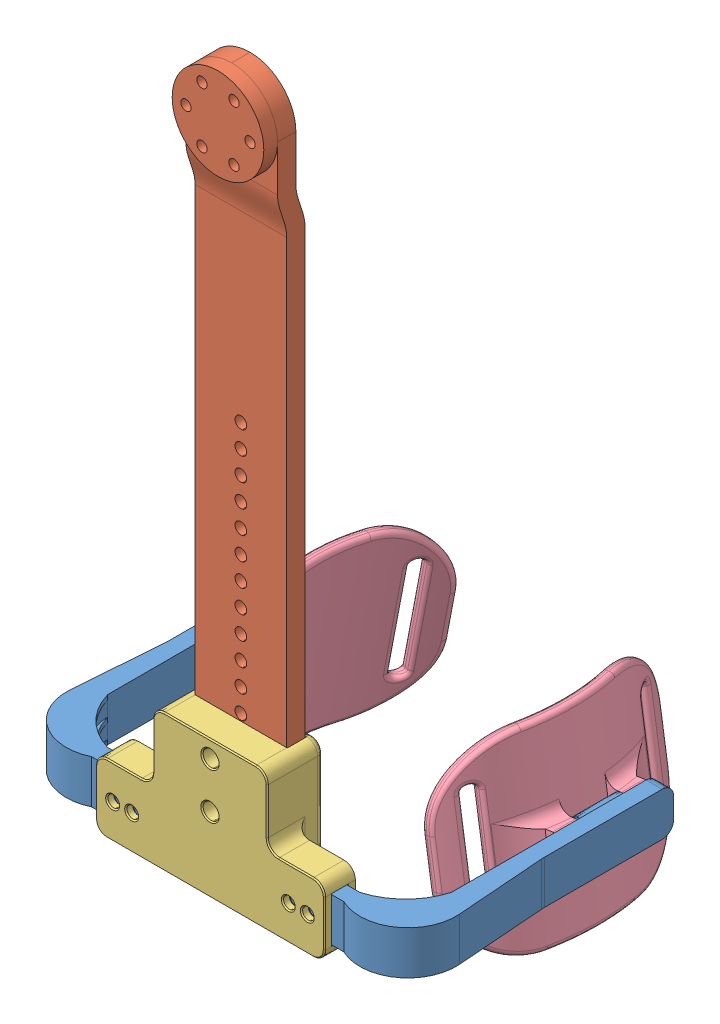
SolidWorks assembly Running_exo_edits_June_10th_2024, configuration Default. Lengths in mm.
Overall size (169.95 340.24 151.32).
6 component instances, 4 part files, 11 mates.
Components (placement in the parent):
- Lshape-thigh_running_v4-2: Lshape-thigh_running_v4 [Default] at (181.1168 78.6919 18.3806) x (0 0 1) z (-1 0 0) size (120 19 75.06)
- Lshape-thigh_running_v4-3: Lshape-thigh_running_v4 [Default] at (17.2912 97.6919 18.6306) x (0 0 1) z (1 0 0) size (120 19 75.06)
- RotorAttachCanted_vertical-2: RotorAttachCanted_vertical [Default] at (98.9386 364.1605 135.1306) x (-1 0 0) z (0 0 -1) size (40 288 18)
- Thigh-TChannel_v5-3: Thigh-TChannel_v5 [Default] at (98.9386 103.1919 126.1306) x (-1 0 0) z (0 0 -1) size (100 60 25)
- slide1WideV3-1: slide1WideV3 [Default] at (85.1951 34.4176 38.3806) x (0 0 1) z (-0.988548 -0.150905 0) size (102.14 80 33)
- slide1WideV3-2: slide1WideV3 [Default] at (126.1843 110.8893 38.6306) x (0 0 1) z (0.982205 -0.187811 0) size (102.14 80 33)
Mates (geometry in assembly coordinates):
- Parallel8: parallel anti-aligned: plane of RotorAttachCanted_vertical-2 through (118.9386 96.1605 125.1306) normal (0 0 1); plane of Thigh-TChannel_v4-3 through (98.9386 73.1919 125.1306) normal (0 0 -1)
- Distance16: distance = 0.25 mm anti-aligned: plane of Thigh-TChannel_v4-3 through (98.9386 78.1919 128.1306) normal (0 0 1); plane of Lshape-thigh_running-2 through (154.1168 97.6919 128.3806) normal (0 0 -1)
- Distance17: distance = 0.5 mm anti-aligned: plane of Thigh-TChannel_v4-3 through (98.9386 98.1919 128.1306) normal (0 -1 0); plane of Lshape-thigh_running-2 through (154.1168 97.6919 108.3806) normal (0 1 0)
- Distance18: distance = 0.5 mm anti-aligned: plane of Lshape-thigh_running-3 through (44.2912 97.6919 108.6306) normal (0 1 0); plane of Thigh-TChannel_v4-3 through (98.9386 98.1919 128.1306) normal (0 -1 0)
- Coincident2: coincident anti-aligned: plane of Lshape-thigh_running_v4-3 through (44.2912 78.6919 135.6306) normal (0 0 1); plane of Thigh-TChannel_v4-3 through (98.9386 78.1919 135.6306) normal (0 0 -1)
- Concentric1: concentric anti-aligned: cylinder of Lshape-thigh_running_v4-2 through (169.1168 87.6919 47.3806) axis (0 0 -1) radius 2.15; cylinder of slide1WideV3-1 through (169.1168 87.6919 12.5823) axis (0 0 1) radius 2.05
- Coincident3: coincident anti-aligned: plane of Lshape-thigh_running_v4-2 through (169.1168 87.6919 28.3806) normal (0 0 -1); plane of slide1WideV3-1 through (174.814 83.5037 28.3806) normal (0 0 1)
- Concentric3: concentric anti-aligned: cylinder of Lshape-thigh_running_v4-3 through (29.2912 88.6919 47.6306) axis (0 0 -1) radius 2.15; cylinder of slide1WideV3-2 through (29.2912 88.6919 12.8323) axis (0 0 1) radius 2.05
- Coincident4: coincident anti-aligned: plane of Lshape-thigh_running_v4-3 through (29.2912 88.6919 28.6306) normal (0 0 -1); plane of slide1WideV3-2 through (25.3192 94.542 28.6306) normal (0 0 1)
- Coincident5: coincident aligned: plane of RotorAttachCanted_vertical-2 through (98.9386 364.1605 135.1306) normal (-1 0 0); plane of Thigh-TChannel_v4-3 through (98.9386 103.1919 126.1306) normal (-1 0 0)
- Coincident6: coincident anti-aligned: plane of RotorAttachCanted_vertical-2 through (118.9386 96.1605 125.1306) normal (0 0 1); plane of Thigh-TChannel_v4-3 through (98.9386 73.1919 125.1306) normal (0 0 -1)
